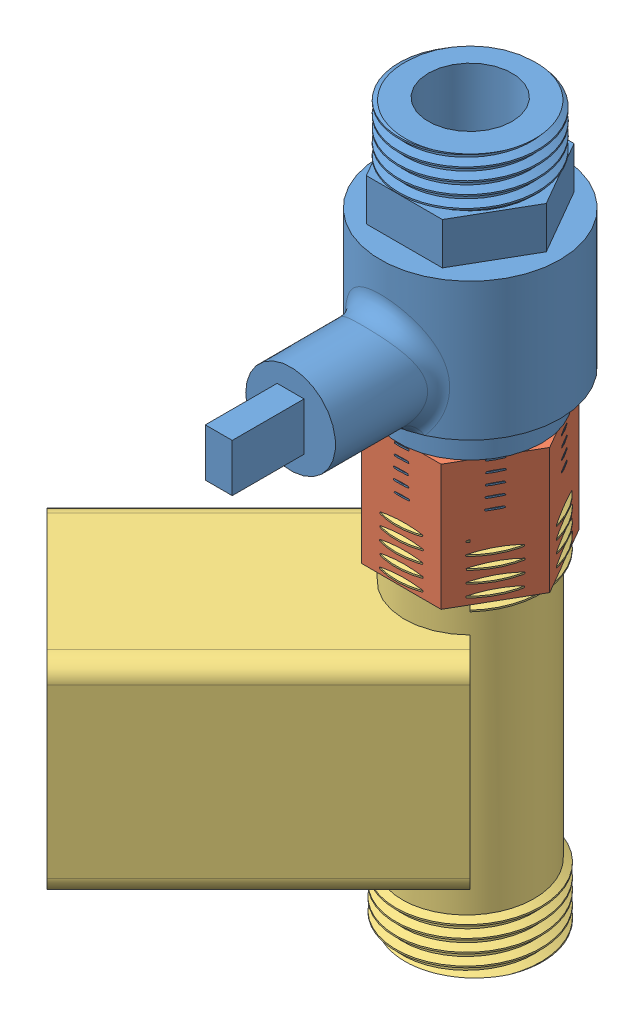
SolidWorks assembly Assemblage2, configuration Défaut. Lengths in mm.
Overall size (68.38 120.37 68.38).
3 component instances, 3 part files, 5 mates.
Components (placement in the parent):
- valve-1: valve [Défaut] at (-30.8692 -20.7184 43.5) size (30 53.36 57)
- raccord_male_male-1: raccord_male_male [Défaut] at (-30.8692 -33.7184 43.5) size (26.56 22.51 23)
- electro_vanne-1: electro_vanne [Défaut] at (-30.8692 -87.7184 43.5) x (-0.707107 0 -0.707107) z (0 1 0) size (34 62.7 64.68)
Mates (geometry in assembly coordinates):
- Coïncidente1: coincident anti-aligned: plane of valve-1 through (-41.3692 -12.7184 43.5) normal (0 -1 0); plane of raccord_male_male-1 through (-30.8692 -12.7184 43.5) normal (0 1 0)
- Coaxiale1: concentric anti-aligned: cylinder of valve-1 through (-30.8692 31.9657 43.5) axis (0 -1 0) radius 7; cylinder of raccord_male_male-1 through (-30.8692 -13.7184 43.5) axis (0 1 0) radius 10.5
- Coaxiale2: concentric anti-aligned: cylinder of valve-1 through (-30.8692 31.2816 43.5) axis (0 1 0) radius 15; cylinder of electro_vanne-1 through (-30.8692 -23.7184 43.5) axis (0 -1 0) radius 11
- Distance1: distance = 10 mm anti-aligned: plane of electro_vanne-1 through (-30.8692 -23.7184 43.5) normal (0 1 0); plane of raccord_male_male-1 through (-30.8692 -33.7184 43.5) normal (0 -1 0)
- Angle1: planar angle = 0.785398 rad anti-aligned: plane of electro_vanne-1 through (-54.2037 -69.7184 90.8762) normal (0.707107 0 0.707107); plane of valve-1 through (-33.1192 3.7816 85.5) normal (-1 0 0)
